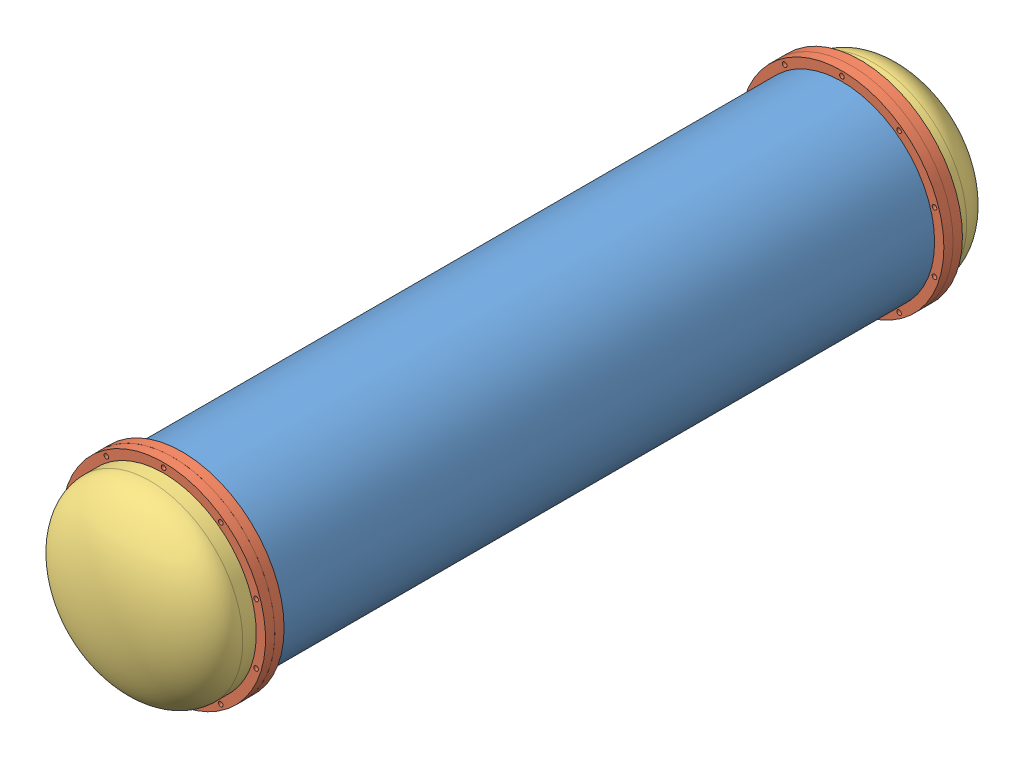
SolidWorks assembly Сборка3, configuration Default. Lengths in mm.
Overall size (257.4 257.4 1032.5).
10 component instances, 3 part files, 4 mates.
Components (placement in the parent):
- 22222-1: 22222 [Default] at (-601.8093 406.3137 381.9778) size (257.4 257.4 856)
  - Обічайка1-1: Обічайка1 [По умолчанию] at (892.2668 99.0076 678.5911) size (234 234 856)
  - флянець-1: флянець [По умолчанию] at (892.2668 99.0076 678.5911) size (257.4 257.4 11.7)
  - флянець-2: флянець [По умолчанию] at (892.2668 99.0076 -165.7089) size (257.4 257.4 11.7)
- 1111-1: 1111 [Default] at (89.0947 350.2875 1108.4429) x (0 0 -1) z (1 0 0) size (88.25 257.4 257.4)
  - кришка1-1: кришка1 [По умолчанию] at (19.1241 155.0338 201.3627) size (88.25 234 234)
  - флянець-1: флянець [По умолчанию] at (47.8741 155.0338 201.3627) x (0 0 -1) z (1 0 0) size (257.4 257.4 11.7)
- 1111-2: 1111 [Default] at (491.8202 350.2875 156.6948) x (0 0 1) z (-1 0 0) size (88.25 257.4 257.4)
  - кришка1-1: кришка1 [По умолчанию] at (19.1241 155.0338 201.3627) size (88.25 234 234)
  - флянець-1: флянець [По умолчанию] at (47.8741 155.0338 201.3627) x (0 0 -1) z (1 0 0) size (257.4 257.4 11.7)
Mates (geometry in assembly coordinates):
- Совпадение2: coincident: circle of 22222-1/флянець-1; circle of 1111-1/флянець-1
- Совпадение5: coincident: circle of 22222-1/флянець-2; circle of ?
- Концентричный1: concentric aligned: cylinder of 22222-1/флянець-2 through (362.6669 604.709 204.5689) axis (0 0 1) radius 2.925; cylinder of 1111-2/флянець-1 through (362.6669 604.709 192.8689) axis (0 0 1) radius 2.925
- Концентричный2: concentric anti-aligned: cylinder of 22222-1/флянець-1 through (362.6669 604.709 1048.8689) axis (0 0 1) radius 2.925; cylinder of 1111-1/флянець-1 through (362.6669 604.709 1072.2689) axis (0 0 -1) radius 2.925
